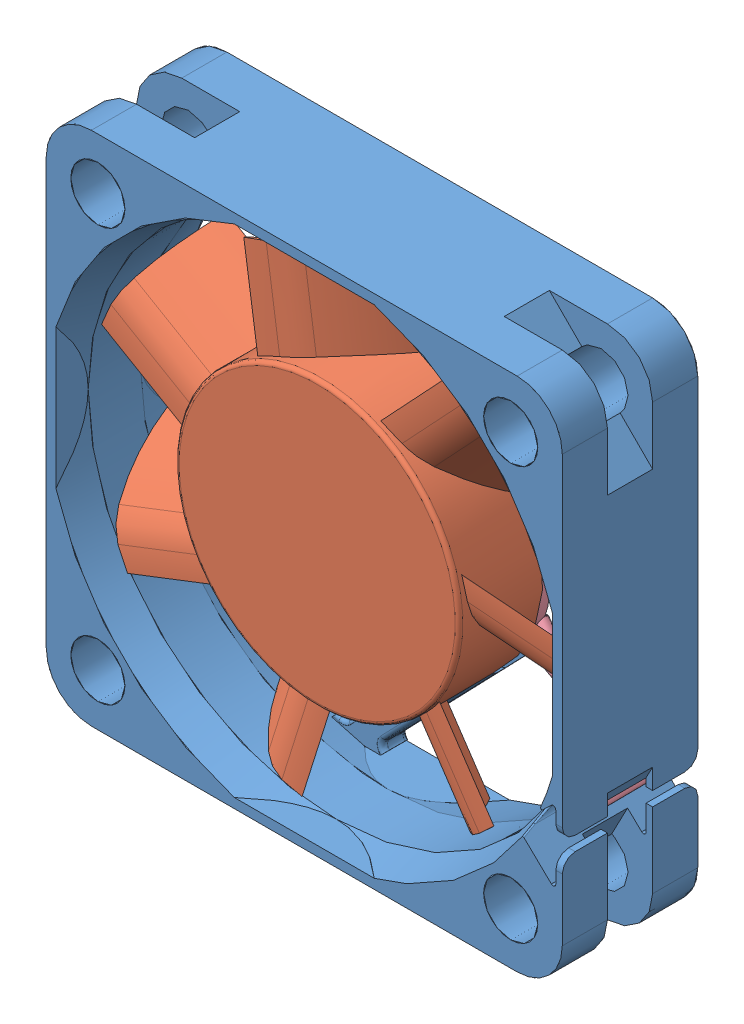
SolidWorks assembly Cooler 40x40x10 SBORKA, configuration Default. Lengths in mm.
Overall size (43.67 40 11.58).
5 component instances, 5 part files, 8 mates.
Components (placement in the parent):
- Cooler 40x40x10 body-1: Cooler 40x40x10 body [Default] at (29.9615 22.174 11.8964) size (40 40 11.58)
- Cooler Blades-1: Cooler Blades [Default] at (29.9615 22.174 14.8964) x (0.079489 0.996836 0) z (0 0 1) size (36.5 36.5 8.5)
- Cooler Motor-1: Cooler Motor [Default] at (29.9615 22.174 11.8964) size (18 18 8.5)
- Cooler pcb-1: Cooler pcb [Default] at (29.9615 22.174 14.8964) x (-0.878553 0.477645 0) z (0 0 -1) size (31.84 21.5 5.61)
- Sticker SUNON-1: Sticker SUNON [Default] at (29.9615 22.174 11.8964) x (-0.001413 -0.999999 0) z (0 0 -1) size (18 18 0.07)
Mates (geometry in assembly coordinates):
- Совпадение2: coincident anti-aligned: plane of Cooler 40x40x10 body-1 through (29.9615 22.174 13.8964) normal (0 0 1); plane of Cooler pcb-1 through (29.9615 22.174 13.8964) normal (0 0 -1)
- Концентричный1: concentric aligned: cylinder of Cooler 40x40x10 body-1 through (29.9615 22.174 22.3964) axis (0 0 -1) radius 2.75; cylinder of Cooler pcb-1 through (29.9615 22.174 14.8964) axis (0 0 -1) radius 3
- Концентричный2: concentric aligned: cylinder of Cooler 40x40x10 body-1 through (29.9615 22.174 22.3964) axis (0 0 -1) radius 2.75; cylinder of Cooler Motor-1 through (29.9615 22.174 14.8964) axis (0 0 -1) radius 2.75
- Совпадение4: coincident aligned: plane of Cooler 40x40x10 body-1 through (46.4615 38.674 11.8964) normal (0 0 -1); plane of Cooler Motor-1 through (29.9615 22.174 11.8964) normal (0 0 -1)
- Совпадение6: coincident anti-aligned: plane of Cooler 40x40x10 body-1 through (46.4615 38.674 11.8964) normal (0 0 -1); plane of Sticker SUNON-1 through (29.9615 22.174 11.8964) normal (0 0 1)
- Концентричный3: concentric anti-aligned: cylinder of Cooler 40x40x10 body-1 through (29.9615 22.174 13.8964) axis (0 0 -1) radius 11; cylinder of Sticker SUNON-1 through (29.9615 22.174 11.8464) axis (0 0 1) radius 9
- Концентричный4: concentric aligned: cylinder of Cooler Blades-1 through (29.9615 22.174 12.8964) axis (0 0 1) radius 0.7; cylinder of Cooler Motor-1 through (29.9615 22.174 12.8964) axis (0 0 1) radius 0.75
- Расстояние3: distance = 1 mm aligned: plane of Cooler Blades-1 through (29.9615 22.174 21.3964) normal (0 0 1); plane of Cooler 40x40x10 body-1 through (46.4615 38.674 22.3964) normal (0 0 1)
